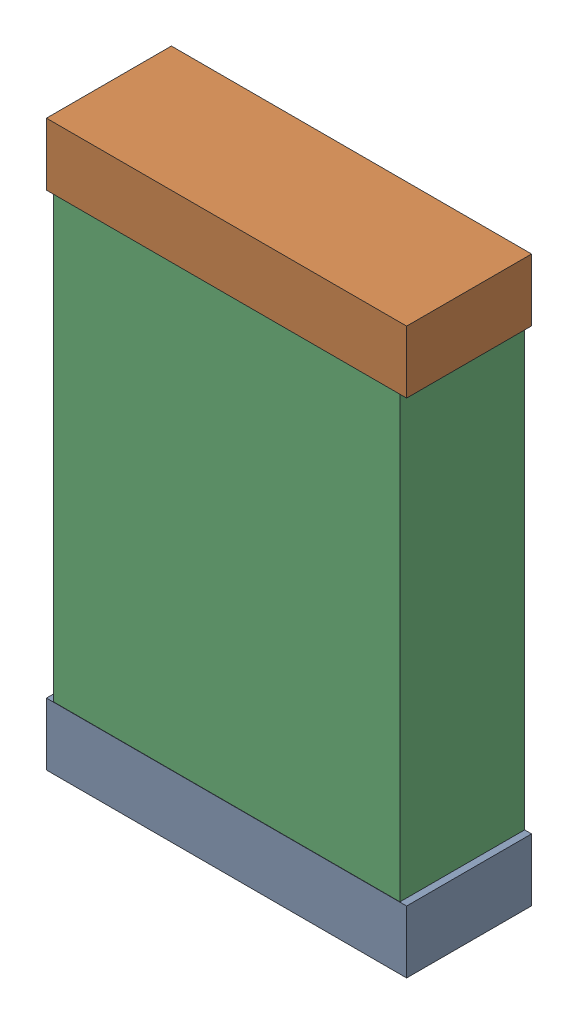
SolidWorks assembly C46, configuration Default. Lengths in mm.
Overall size (1.3 2.04 0.45).
6 component instances, 2 part files, 0 mates.
Components (placement in the parent):
- 740902240-1: 740902240 [Default] at (76.9612 21.3736 0) size (1.3 0.23 0.45)
  - Extruded_35-1: Extruded_35 [Default] at origin size (1.3 0.23 0.45)
- 740902240-2: 740902240 [Default] at (76.9612 23.1861 0) size (1.3 0.23 0.45)
  - Extruded_35-1: Extruded_35 [Default] at origin size (1.3 0.23 0.45)
- 740904480-1: 740904480 [Default] at (76.9612 22.2736 0) size (1.25 2 0.45)
  - Extruded_34-1: Extruded_34 [Default] at origin size (1.25 2 0.45)
